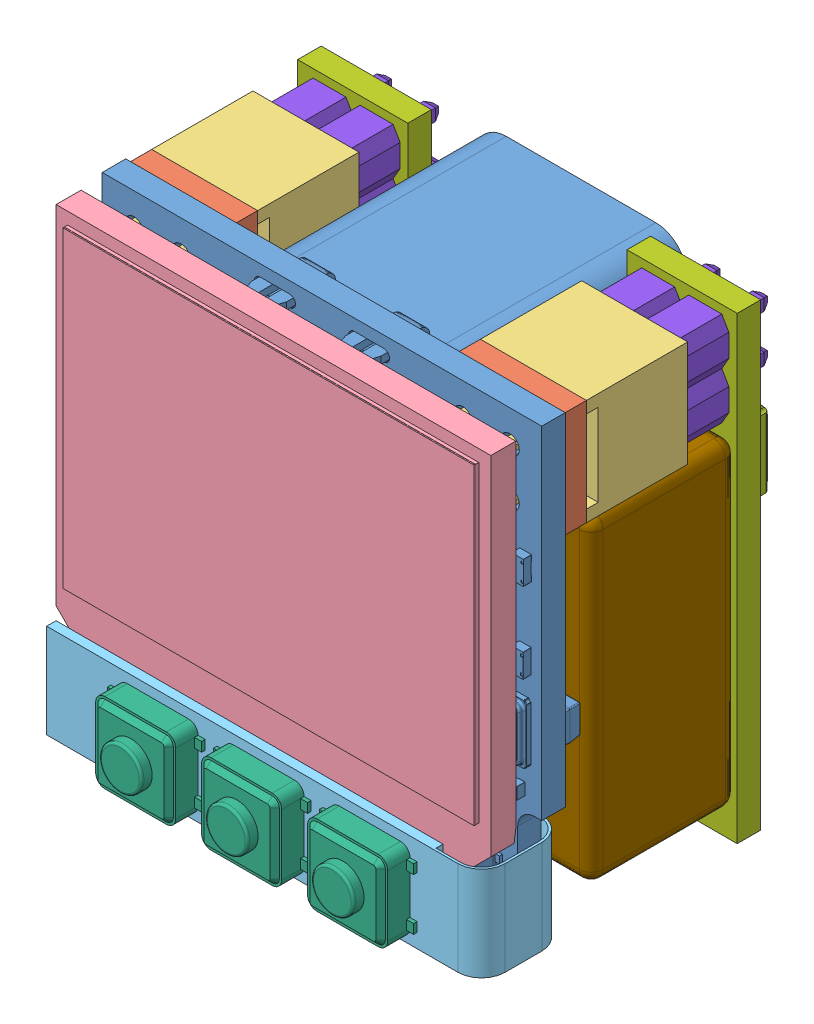
SolidWorks assembly SAU-G0+EX_AHT-GL_PCB, configuration 默认. Lengths in mm.
Overall size (20.36 19.5 16.16).
17 component instances, 9 part files, 6 mates.
Components (placement in the parent):
- SAU-G0_PCB-1: SAU-G0_PCB [默认] at (11.5169 60.6772 -14.7107) size (20.36 19.5 15.06)
  - SAU-G0_STEP_AD-1: SAU-G0_STEP_AD [默认] at (-16.5787 -13.328 24.4103) size (18.66 19.5 12.19)
  - 2.00mm_2x2_垫板PCB_厚1.0mm-1: 2.00mm_2x2_垫板PCB_厚1.0mm [默认] at (3.1013 6.262 22.4106) x (1 0 0) z (0 -1 0) size (4.5 1 4.5)
  - 2.00mm母座2x2-1: 2.00mm母座2x2 [Default] at (4.1013 6.262 18.1106) x (1 0 0) z (0 1 0) size (4.5 7.1 4.5)
  - 2.00mm_2x2_垫板PCB_厚1.0mm-2: 2.00mm_2x2_垫板PCB_厚1.0mm [默认] at (-10.8587 6.262 22.4106) x (-1 0 0) z (0 1 0) size (4.5 1 4.5)
  - 2.00mm母座2x2-2: 2.00mm母座2x2 [Default] at (-11.8587 6.262 18.1106) x (-1 0 0) z (0 -1 0) size (4.5 7.1 4.5)
  - 0.66寸_64x48_TOP_FPC背面距离背板1mm-1: 0.66寸_64x48_TOP_FPC背面距离背板1mm [Default] at (-3.8787 8.514 25.9703) x (1 0 0) z (0 -1 0) size (18.46 2.27 19.3)
  - 轻触开关+柔性PCB-1: 轻触开关+柔性PCB [默认] at (-0.958 10.42 26.3367) x (1 0 0) z (0 -1 0) size (20.26 5.16 4.01)
    - 方案2-轻触开关_柔性PCB-1: 方案2-轻触开关_柔性PCB [默认] at (-12.1506 0.4339 17.21) size (20.26 3.56 4.01)
    - 轻触开关3x3.5x1.5_3x4.0x2.0-1: 轻触开关3x3.5x1.5_3x4.0x2.0 [默认] at (-2.9206 0.5339 19.31) size (4 1.6 3.4)
    - 轻触开关3x3.5x1.5_3x4.0x2.0-2: 轻触开关3x3.5x1.5_3x4.0x2.0 [默认] at (1.5794 0.5339 19.31) size (4 1.6 3.4)
    - 轻触开关3x3.5x1.5_3x4.0x2.0-3: 轻触开关3x3.5x1.5_3x4.0x2.0 [默认] at (-7.4206 0.5339 19.31) size (4 1.6 3.4)
- SAU-G0-EX_AHT-GL_PCB-1: SAU-G0-EX_AHT-GL_PCB [默认] at (7.6382 62.4703 19.0392) x (-1 0 0) z (0 0 -1) size (18.66 19.5 9.5)
  - SAU-G0-EX_AHT-GL_STEP_AD-1: SAU-G0-EX_AHT-GL_STEP_AD [默认] at (33.02 -15.1211 17.6394) x (-1 0 0) z (0 0 -1) size (18.66 19.5 3.8)
  - 2.0mm排针2x2-1: 2.0mm排针2x2 [Default] at (-7.9796 3.4685 17.6394) x (-1 0 0) z (0 -1 0) size (4 8.2 4)
  - 2.0mm排针2x2-2: 2.0mm排针2x2 [Default] at (7.9796 5.4685 17.6394) x (1 0 0) z (0 1 0) size (4 8.2 4)
- 601419(18.5x13.5x6.2mm)_3.7V_100mAh-1: 601419(18.5x13.5x6.2mm)_3.7V_100mAh [Default] at (16.9702 57.9392 3.2499) x (0 -1 0) z (-1 0 0) size (13.5 6.2 18)
Mates (geometry in assembly coordinates):
- 重合1: coincident anti-aligned: plane of SAU-G0-EX_AHT-GL_PCB-1/2.0mm排针2x2-2 through (-0.3414 67.9389 3.3999) normal (0 0 1); plane of SAU-G0_PCB-1/2.00mm母座2x2-2 through (-1.3418 64.6892 3.3999) normal (0 0 -1)
- 重合2: coincident aligned: plane of SAU-G0_PCB-1/SAU-G0_STEP_AD-1 through (-1.6938 49.7872 8.6999) normal (-1 0 0); plane of SAU-G0-EX_AHT-GL_PCB-1/SAU-G0-EX_AHT-GL_STEP_AD-1 through (-1.6938 49.7872 0.4002) normal (-1 0 0)
- 重合3: coincident aligned: plane of SAU-G0_PCB-1/SAU-G0_STEP_AD-1 through (-1.6938 69.2912 8.6999) normal (0 1 0); plane of SAU-G0-EX_AHT-GL_PCB-1/SAU-G0-EX_AHT-GL_STEP_AD-1 through (-1.6938 69.2912 0.4002) normal (0 1 0)
- 重合7: coincident anti-aligned: plane of SAU-G0-EX_AHT-GL_PCB-1/SAU-G0-EX_AHT-GL_STEP_AD-1 through (-1.6938 49.7872 1.3999) normal (0 0 1); plane of 601419(18.5x13.5x6.2mm)_3.7V_100mAh-1 through (16.9702 51.1892 1.3999) normal (0 0 -1)
- 重合8: coincident anti-aligned: plane of SAU-G0_PCB-1/2.00mm母座2x2-2 through (-1.3418 64.6892 3.3999) normal (0 -1 0); plane of 601419(18.5x13.5x6.2mm)_3.7V_100mAh-1 through (16.9702 64.6892 3.2499) normal (0 1 0)
- 重合9: coincident aligned: plane of SAU-G0_PCB-1/SAU-G0_STEP_AD-1 through (16.9702 69.2912 8.6999) normal (1 0 0); plane of 601419(18.5x13.5x6.2mm)_3.7V_100mAh-1 through (16.9702 51.1892 1.3999) normal (1 0 0)
